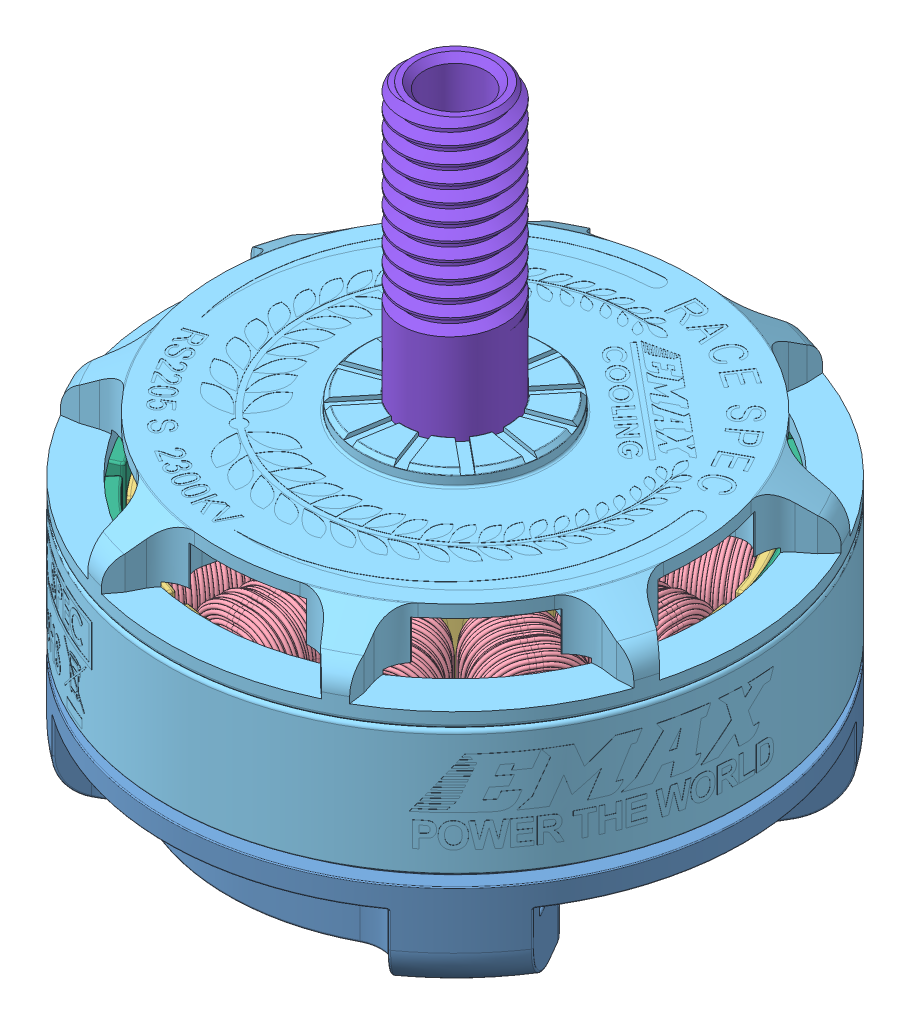
SolidWorks assembly EMAX RS2205S, configuration Predeterminado. Lengths in mm.
Overall size (39.3 30.6 39.3).
24 component instances, 10 part files, 11 mates.
Components (placement in the parent):
- STATOR-1: STATOR [Predeterminado] at origin size (27.9 11.97 27.9)
  - STATOR-1: STATOR [Predeterminado] at origin size (27.9 10.76 27.9)
  - BEARING-1: BEARING [Predeterminado] at (0 1.95 0) x (1 0 0) z (0 1 0) size (8 8 3.5)
  - BEARING-2: BEARING [Predeterminado] at (0 8.85 0) x (-0.982082 0 -0.188455) z (0 -1 0) size (8 8 3.5)
  - STATOR SLEEVE-1: STATOR SLEEVE [Predeterminado] at (0 5.25 0) size (22.5 5.67 22.5)
  - WINDING-1: WINDING [Predeterminado] at (8.4112 8.075 0) size (4.68 7.47 4.47)
  - WINDING-2: WINDING [Predeterminado] at (7.2843 8.075 4.2056) x (0.866025 0 0.5) z (-0.5 0 0.866025) size (4.68 7.47 4.47)
  - WINDING-3: WINDING [Predeterminado] at (4.2056 8.075 7.2843) x (0.5 0 0.866025) z (-0.866025 0 0.5) size (4.68 7.47 4.47)
  - WINDING-4: WINDING [Predeterminado] at (0 8.075 8.4112) x (0 0 1) z (-1 0 0) size (4.68 7.47 4.47)
  - WINDING-5: WINDING [Predeterminado] at (-4.2056 8.075 7.2843) x (-0.5 0 0.866025) z (-0.866025 0 -0.5) size (4.68 7.47 4.47)
  - WINDING-6: WINDING [Predeterminado] at (-7.2843 8.075 4.2056) x (-0.866025 0 0.5) z (-0.5 0 -0.866025) size (4.68 7.47 4.47)
  - WINDING-7: WINDING [Predeterminado] at (-8.4112 8.075 0) x (-1 0 0) z (0 0 -1) size (4.68 7.47 4.47)
  - WINDING-8: WINDING [Predeterminado] at (-7.2843 8.075 -4.2056) x (-0.866025 0 -0.5) z (0.5 0 -0.866025) size (4.68 7.47 4.47)
  - WINDING-9: WINDING [Predeterminado] at (-4.2056 8.075 -7.2843) x (-0.5 0 -0.866025) z (0.866025 0 -0.5) size (4.68 7.47 4.47)
  - WINDING-10: WINDING [Predeterminado] at (0 8.075 -8.4112) x (0 0 -1) z (1 0 0) size (4.68 7.47 4.47)
  - WINDING-11: WINDING [Predeterminado] at (4.2056 8.075 -7.2843) x (0.5 0 -0.866025) z (0.866025 0 0.5) size (4.68 7.47 4.47)
  - WINDING-12: WINDING [Predeterminado] at (7.2843 8.075 -4.2056) x (0.866025 0 -0.5) z (0.5 0 0.866025) size (4.68 7.47 4.47)
- ROTOR-1: ROTOR [Predeterminado] at (0 0.05 0) x (0.771425 0 0.636321) z (-0.636321 0 0.771425) size (27.91 28.74 27.91)
  - ROTOR BELL-1: ROTOR BELL [Predeterminado] at origin size (27.91 10.2 27.91)
  - MAGNETS-1: MAGNETS [Predeterminado] at (0 5.3 0) size (25.73 6 25.8)
  - MAGNETS ADHESIVE-1: MAGNETS ADHESIVE [Predeterminado] at (0 5.4 0) size (26 5.9 26)
  - SHAFT-1: SHAFT [Predeterminado] at (0 0.2 0) size (7.2 28.74 7.2)
- WASHER-1: WASHER [Predeterminado] at (0 -0.6 0) x (0.636321 0 -0.771425) z (0.771425 0 0.636321) size (5 0.8 5)
- SCREW-3: SCREW [ROSCADO] at (0 3.4 0) x (0 1 0) z (-0.946141 0 -0.323755) size (5.25 3.8 3.8)
Mates (geometry in assembly coordinates):
- Coincidente1: coincident: plane of STATOR-1/STATOR-1 through (0 0 0) normal (0 0 1); plane of assembly through (0 0 0) normal (0 0 1)
- Coincidente2: coincident: plane of STATOR-1/STATOR-1 through (-11.95 0 0) normal (0 -1 0); plane of assembly through (0 0 0) normal (0 1 0)
- Coincidente3: coincident: plane of STATOR-1/STATOR-1 through (0 0 0) normal (1 0 0); plane of assembly through (0 0 0) normal (1 0 0)
- Concéntrica1: concentric: cylinder of STATOR-1/STATOR-1 through (0 0 0) axis (0 -1 0) radius 13.95; cylinder of ROTOR-1/ROTOR BELL-1 through (0 0.05 0) axis (0 -1 0) radius 13.95
- Coincidente6: coincident: plane of STATOR-1/BEARING-2 through (0.3644 10.6 -1.8989) normal (0 1 0); plane of ROTOR-1/SHAFT-1 through (2.2371 10.6 1.8453) normal (0 -1 0)
- Concéntrica2: concentric: cylinder of ROTOR-1/SHAFT-1 through (0 0.25 0) axis (0 -1 0) radius 0.8; cylinder of WASHER-1 through (0 0.2 0) axis (0 -1 0) radius 1.1
- Concéntrica41: concentric: cone of WASHER-1 through (0 -0.6 0) axis (0 1 0); cylinder of SCREW-3 through (0 3.4 0) axis (0 1 0) radius 1.9
- Coincidente91: coincident: plane of WASHER-1 through (0 -0.6 0) normal (0 -1 0); plane of SCREW-3 through (0.3561 -0.6 -1.0408) normal (0 1 0)
- Bloquear1: lock: unknown of ?; unknown of SCREW-3
- Bloquear2: lock: unknown of ?; unknown of WASHER-1
- Coincidente93: coincident: plane of STATOR-1/BEARING-1 through (0 0.2 -1.9336) normal (0 -1 0); plane of WASHER-1 through (0 0.2 0) normal (0 1 0)
